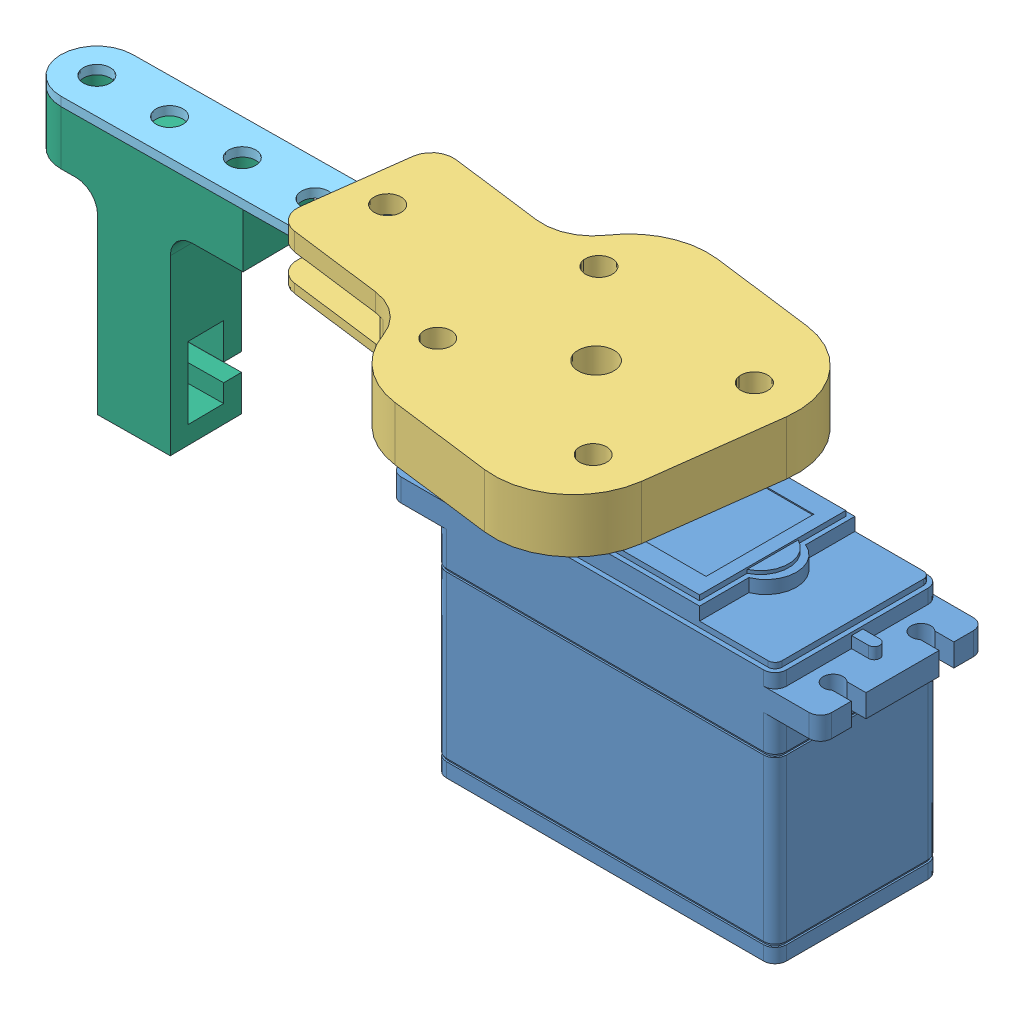
SolidWorks assembly Throttle Assembly, configuration Default. Lengths in mm.
Overall size (153.45 63.52 59.71).
6 component instances, 6 part files, 12 mates.
Components (placement in the parent):
- SERVO MOTOR HITEC HS-785HB-1: SERVO MOTOR HITEC HS-785HB [Default] at (32.474 20.5722 51.9843) size (76 50.5 29)
- ServoGear-1: ServoGear [Default] at (16.474 72.0722 51.9843) x (-0.127663 0 0.991818) z (-0.991818 0 -0.127663) size (6 13.5 6)
- servo4waylock3.0-1: servo4waylock3.0 [Default] at (40.3687 79.3347 55.1077) x (0.991818 0 0.127663) z (-0.127663 0 0.991818) size (73.03 9.53 50.8)
- Servo4Way-1: Servo4Way [Default] at (16.4362 71.3972 52.0272) x (-0.127663 0 0.991818) z (-0.991818 0 -0.127663) size (42.86 6.35 44.45)
- 5holeExtension-1: 5holeExtension [Default] at (-51.1594 77.1233 46.8516) x (0.999949 0 -0.010072) z (0.010072 0 0.999949) size (63.5 1.59 12.7)
- cableMount-1: cableMount [Default] at (-63.8588 77.1233 46.9795) x (-0.999949 0 0.010072) z (-0.010072 0 -0.999949) size (38.1 43.91 12.7)
Mates (geometry in assembly coordinates):
- Concentric1: concentric aligned: cylinder of SERVO MOTOR HITEC HS-785HB-1 through (16.474 61.0722 51.9843) axis (0 1 0) radius 1.5; cylinder of ServoGear-1 through (16.474 61.0722 51.9843) axis (0 1 0) radius 0.75
- Coincident1: coincident anti-aligned: plane of SERVO MOTOR HITEC HS-785HB-1 through (16.474 61.0722 51.9843) normal (0 1 0); plane of ServoGear-1 through (16.474 61.0722 51.9843) normal (0 -1 0)
- Coincident2: coincident anti-aligned: plane of ServoGear-1 through (17.8297 74.5722 51.4182) normal (0.922771 0 -0.385349); plane of Servo4Way-1 through (17.8393 74.5722 51.4413) normal (-0.922771 0 0.385349)
- Coincident3: coincident anti-aligned: plane of ServoGear-1 through (15.2874 74.5722 51.0793) normal (-0.795107 0 -0.606469); plane of Servo4Way-1 through (15.2528 74.5722 51.1246) normal (0.795107 0 0.606469)
- Coincident4: coincident anti-aligned: plane of ServoGear-1 through (16.474 74.5722 51.9843) normal (0 1 0); plane of Servo4Way-1 through (16.4362 74.5722 52.0272) normal (0 -1 0)
- Concentric2: concentric anti-aligned: cylinder of servo4waylock3.0-1 through (16.4362 84.0972 52.0272) axis (0 -1 0) radius 3.175; cylinder of Servo4Way-1 through (16.4362 76.1597 52.0272) axis (0 1 0) radius 3.175
- Concentric3: concentric anti-aligned: cylinder of servo4waylock3.0-1 through (14.5109 77.7472 66.9851) axis (0 -1 0) radius 6.35; cylinder of Servo4Way-1 through (14.5109 76.1597 66.9851) axis (0 1 0) radius 6.35
- Coincident5: coincident anti-aligned: plane of servo4waylock3.0-1 through (40.3687 77.7472 55.1077) normal (0 -1 0); plane of Servo4Way-1 through (0.6911 77.7472 50.0006) normal (0 1 0)
- Concentric4: concentric anti-aligned: cylinder of servo4waylock3.0-1 through (-25.7607 74.5722 46.5958) axis (0 1 0) radius 2.3813; cylinder of 5holeExtension-1 through (-25.7607 78.7108 46.5958) axis (0 -1 0) radius 2.3813
- Coincident6: coincident: plane of 5holeExtension-1 through (-25.7607 77.1233 46.5958) normal (0 -1 0); plane of cableMount-1 through (-76.393 77.1233 43.949) normal (0 1 0)
- Concentric5: concentric: cylinder of 5holeExtension-1 through (-51.1594 78.7108 46.8516) axis (0 -1 0) radius 2.3813; cylinder of cableMount-1 through (-51.1594 77.1233 46.8516) axis (0 -1 0) radius 2.3813
- Concentric6: concentric aligned: cylinder of 5holeExtension-1 through (-76.5581 78.7108 47.1074) axis (0 -1 0) radius 2.3813; cylinder of cableMount-1 through (-76.5581 77.1233 47.1074) axis (0 -1 0) radius 2.3813
